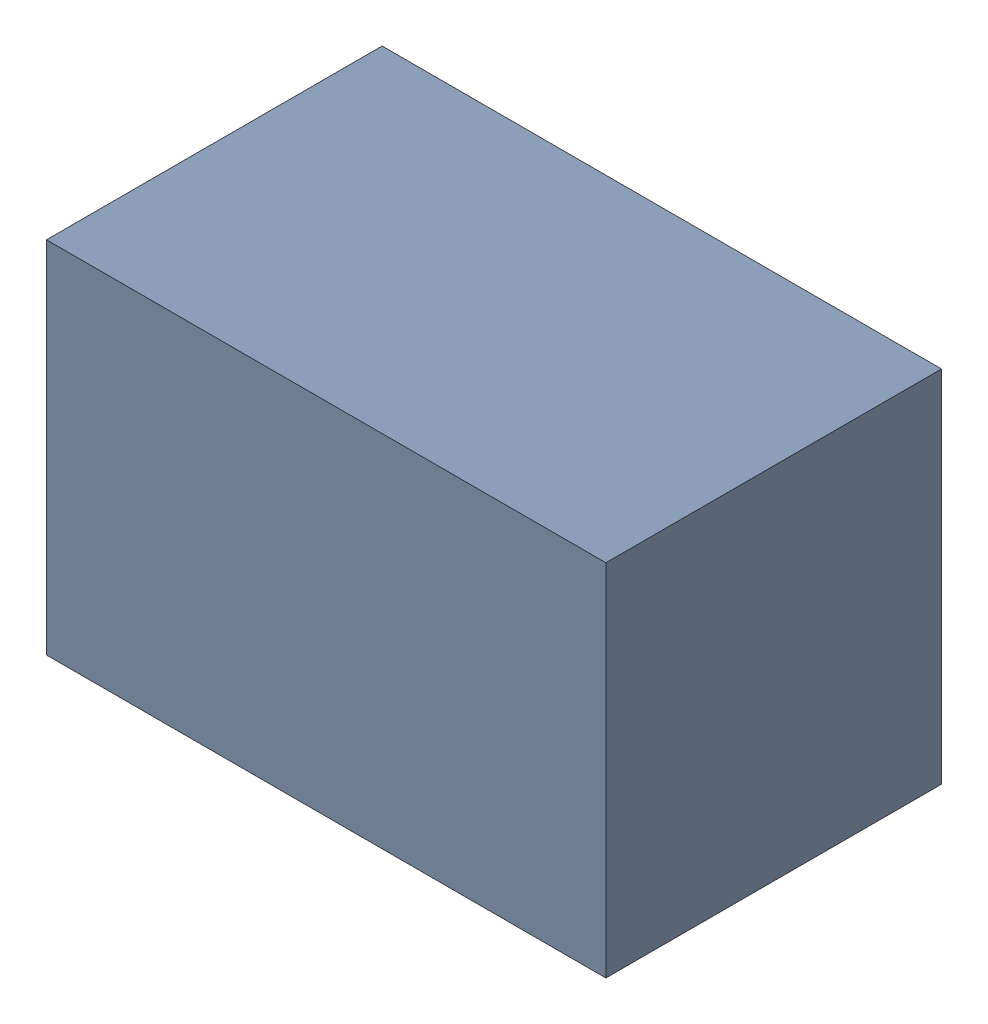
SolidWorks assembly C5_1, configuration Default. Lengths in mm.
Overall size (2.1 1.35 1.26).
2 component instances, 1 part files, 0 mates.
Components (placement in the parent):
- 407985824_1-1: 407985824_1 [Default] at (35.814 4.699 0.0127) size (2.1 1.35 1.26)
  - Extruded_7-1: Extruded_7 [Default] at origin size (2.1 1.35 1.26)
